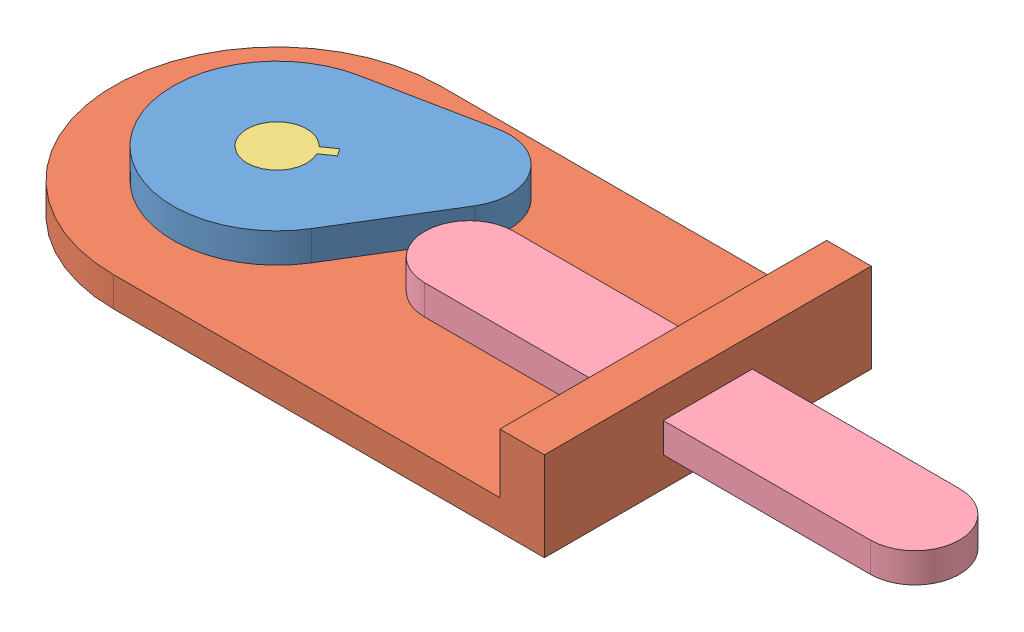
SolidWorks assembly Assem2, configuration Default. Lengths in mm.
Overall size (284.7 30 118.72).
4 component instances, 4 part files, 10 mates.
Components (placement in the parent):
- cam-1: cam [Default] at (-145 10 55) x (0.819822 0 -0.572618) z (0.572618 0 0.819822) size (96.16 10 70)
- cam_base-1: cam_base [Default] at (-85.1815 10 27.1774) x (1 0 0) z (0 1 0) size (200 110 30)
- cam_pin-1: cam_pin [Default] at (-100.9916 10 2.6541) x (0.819822 0 -0.572618) z (0.572618 0 0.819822) size (24.88 20 19.99)
- can_bar-1: can_bar [Default] at (-80.2954 20 55) x (1 0 0) z (0 -1 0) size (180 30 10)
Mates (geometry in assembly coordinates):
- Coincident1: coincident anti-aligned: plane of cam_base-1 through (-85.1815 0 27.1774) normal (0 -1 0)
- Coincident2: coincident: point of cam_base-1
- Coincident3: coincident aligned: plane of cam_base-1 through (0 0 27.1774) normal (1 0 0)
- Concentric2: concentric aligned: cylinder of cam-1 through (-145 20 55) axis (0 -1 0) radius 10; cylinder of cam_pin-1 through (-145 20 55) axis (0 -1 0) radius 9.9965
- Parallel2: parallel anti-aligned: plane of cam-1 through (-132.7954 20 46.4755) normal (-0.819822 0 0.572618); plane of cam_pin-1 through (-142.9418 20 31.955) normal (0.819822 0 -0.572618)
- Coincident6: coincident aligned: plane of cam-1 through (-145 20 55) normal (0 1 0); plane of cam_pin-1 through (-100.9916 20 2.6541) normal (0 1 0)
- Coincident7: coincident aligned: circle of cam_base-1; cylinder of cam_pin-1 through (-145 0 55) axis (0 1 0) radius 5
- Coincident8: coincident aligned: plane of cam_base-1 through (-85.1815 0 27.1774) normal (0 -1 0); plane of cam_pin-1 through (-100.9916 0 2.6541) normal (0 -1 0)
- Coincident9: coincident anti-aligned: plane of cam_base-1 through (-85.1815 10 27.1774) normal (0 1 0); plane of can_bar-1 through (-80.2954 10 55) normal (0 -1 0)
- Coincident10: coincident anti-aligned: plane of cam_base-1 through (-20 20 70) normal (0 0 -1); plane of can_bar-1 through (-80.2954 10 70) normal (0 0 1)
